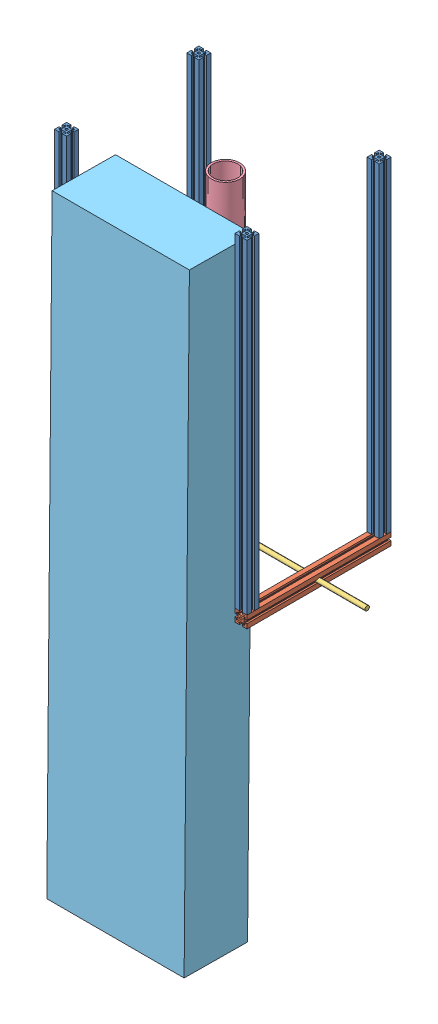
SolidWorks assembly Antenna_Mount, configuration Default. Lengths in mm.
Overall size (609.6 1343.25 379.38).
9 component instances, 5 part files, 0 mates.
Components (placement in the parent):
- 8020_27inch-1: 8020_27inch [Default] at (0 -685.8 -279.4) x (0 0 -1) z (1 0 0) size (25.4 685.8 25.4)
- 8020_27inch-2: 8020_27inch [Default] at (381 -685.8 -279.4) x (0 0 1) z (-1 0 0) size (25.4 685.8 25.4)
- 8020_27inch-3: 8020_27inch [Default] at (0 -685.8 0) x (0 0 -1) z (1 0 0) size (25.4 685.8 25.4)
- 8020_27inch-4: 8020_27inch [Default] at (381 -685.8 0) x (0 0 1) z (-1 0 0) size (25.4 685.8 25.4)
- 8020_12inch-1: 8020_12inch [Default] at (0 -698.5 12.7) x (1 0 0) z (0 1 0) size (25.4 304.8 25.4)
- 8020_12inch-2: 8020_12inch [Default] at (381 -698.5 -292.1) x (1 0 0) z (0 -1 0) size (25.4 304.8 25.4)
- 3_8_Carbon_Steel_Rod-1: 3_8_Carbon_Steel_Rod [Default] at (495.3 -698.5 -139.7) x (0 -0.76673 -0.641969) z (0 0.641969 -0.76673) size (9.53 609.6 9.53)
- 2_inch_PVC-1: 2_inch_PVC [Default] at (190.5 -1272.6456 -134.7434) x (-1 0 0) z (0 -0.008633 -0.999963) size (60.32 1219.2 60.32)
- Antenna-1: Antenna [Default] at (190.5 -1342.1764 20.2311) x (0 -0.008633 -0.999963) z (1 0 0) size (191.26 1290.07 290.07)
